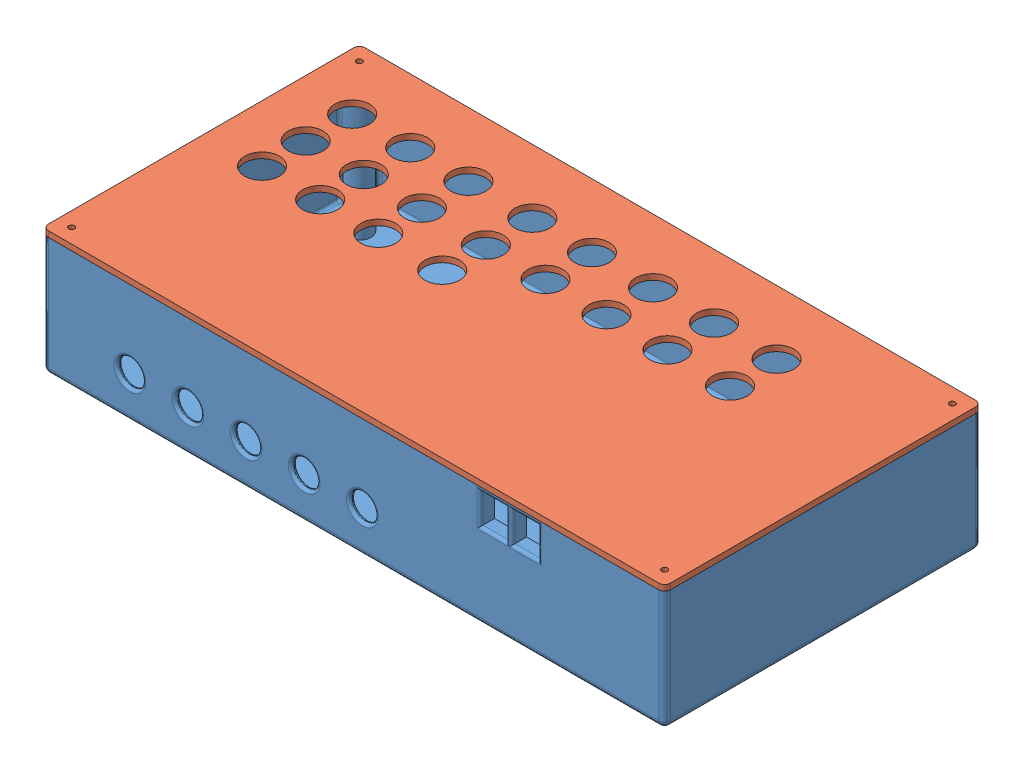
SolidWorks assembly Assem1, configuration Default. Lengths in mm.
Overall size (214 43 109).
2 component instances, 2 part files, 2 mates.
Components (placement in the parent):
- bottom-main-1: bottom-main [Default] at (87.096 62.2326 180.1201) size (214 41 109)
- top-main-1: top-main [Default] at (87.096 103.2326 180.1201) size (214 2 109)
Mates (geometry in assembly coordinates):
- Coincident1: coincident: circle of bottom-main-1; circle of top-main-1
- Coincident2: coincident anti-aligned: circle of bottom-main-1; circle of top-main-1
